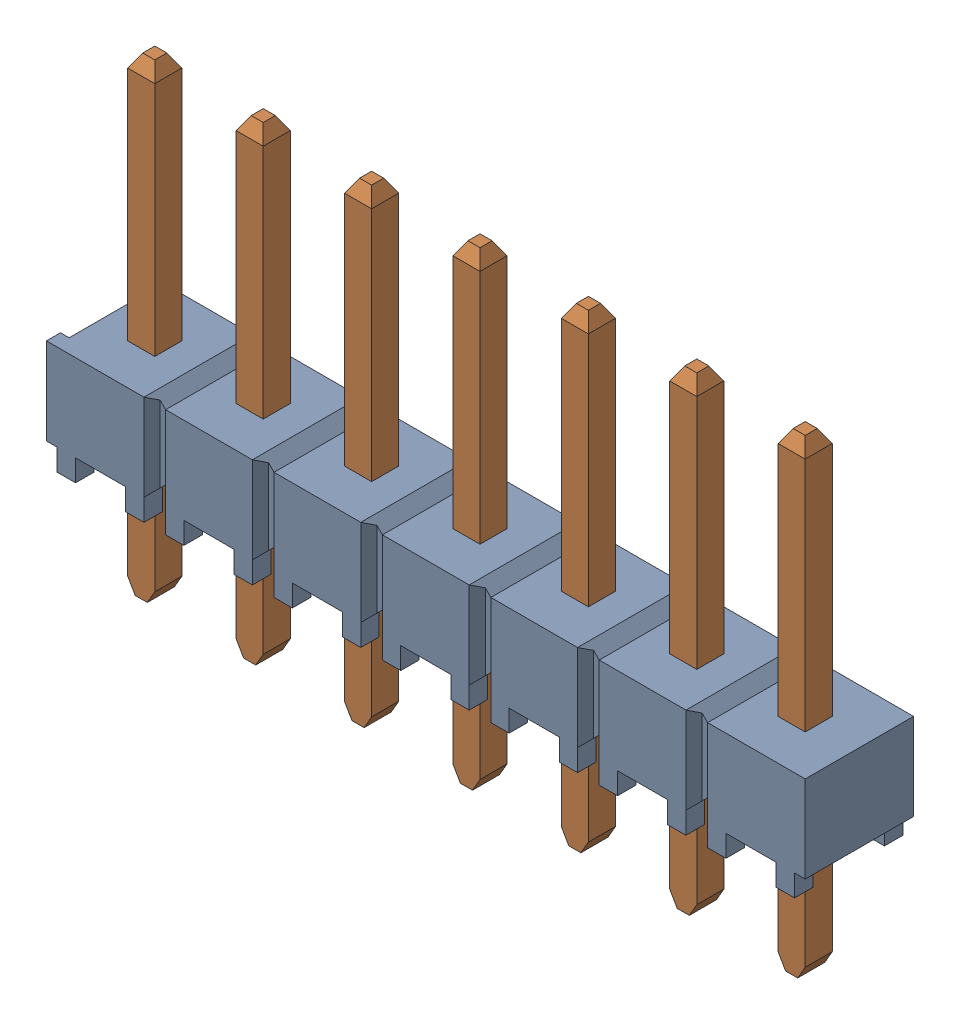
SolidWorks assembly TSW-107-07-G-S, configuration Default. Lengths in mm.
Overall size (17.91 10.92 2.54).
2 component instances, 2 part files, 0 mates.
Components (placement in the parent):
- _TSW-107-07-G-S_body-1: _TSW-107-07-G-S_body [Default] at origin size (17.91 2.54 2.54)
- _T-1S6-07-TSW-1-07-7-S-1: _T-1S6-07-TSW-1-07-7-S [Default] at (0 -2.54 0) size (16.13 10.92 0.89)
